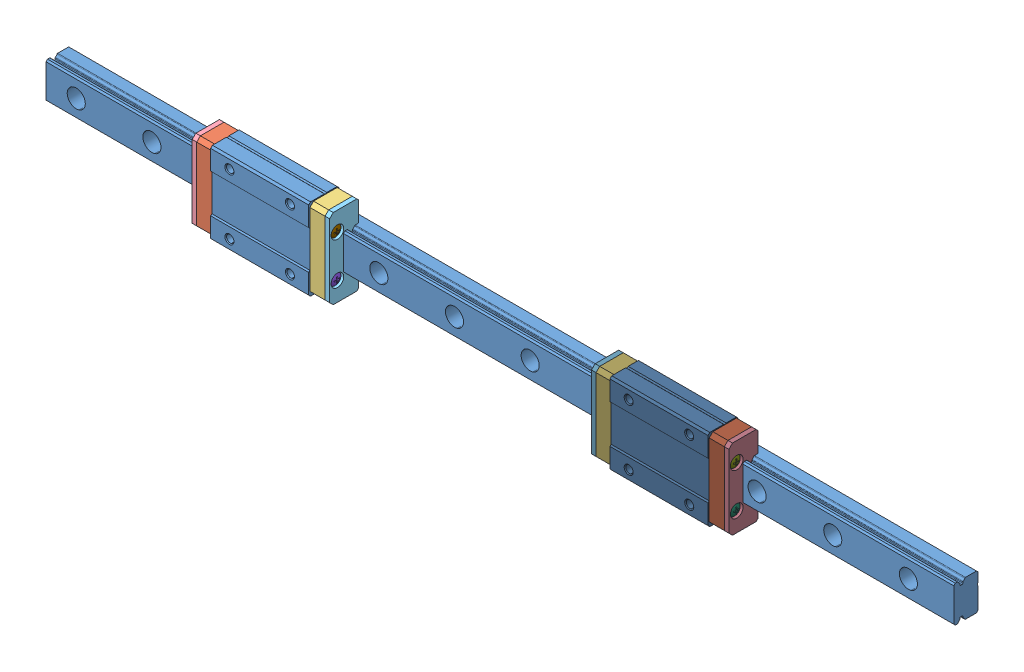
SolidWorks assembly MGN12H2R300ZFC-HiwinCorporation, configuration MGN12H2R300ZFC. Lengths in mm.
Overall size (300 27 13.07).
21 component instances, 19 part files, 9 mates.
Components (placement in the parent):
- Assem2^MGN12H2R300ZFC-HiwinCorporation-1: Assem2^MGN12H2R300ZFC-HiwinCorporation [Default] at (-16.8191 0 0) size (45.6 27 10) (virtual)
  - PRODUCT_ID_1_1-1: PRODUCT_ID_1_1 [Default] at origin size (32.4 27 10)
  - PRODUCT_ID_2_1-1: PRODUCT_ID_2_1 [Default] at origin size (5 26.4 9.6)
  - PRODUCT_ID_3_1-1: PRODUCT_ID_3_1 [Default] at origin size (5 26.4 9.6)
  - PRODUCT_ID_4_1-1: PRODUCT_ID_4_1 [Default] at origin size (1.5 26.4 9.6)
  - PRODUCT_ID_5_1-1: PRODUCT_ID_5_1 [Default] at origin size (1.5 26.4 9.6)
  - PRODUCT_ID_6_1-1: PRODUCT_ID_6_1 [Default] at origin size (1.7 4 4)
  - PRODUCT_ID_7_1-1: PRODUCT_ID_7_1 [Default] at origin size (1.7 4 4)
  - PRODUCT_ID_8_1-1: PRODUCT_ID_8_1 [Default] at origin size (1.7 4 4)
  - PRODUCT_ID_9_1-1: PRODUCT_ID_9_1 [Default] at origin size (1.7 4 4)
- Assem4^MGN12H2R300ZFC-HiwinCorporation-1: Assem4^MGN12H2R300ZFC-HiwinCorporation [Default] at origin size (45.6 27 10) (virtual)
  - PRODUCT_ID_10_1-1: PRODUCT_ID_10_1 [Default] at origin size (32.4 27 10)
  - PRODUCT_ID_11_1-1: PRODUCT_ID_11_1 [Default] at origin size (5 26.4 9.6)
  - PRODUCT_ID_12_1-1: PRODUCT_ID_12_1 [Default] at origin size (5 26.4 9.6)
  - PRODUCT_ID_13_1-1: PRODUCT_ID_13_1 [Default] at origin size (1.5 26.4 9.6)
  - PRODUCT_ID_14_1-1: PRODUCT_ID_14_1 [Default] at origin size (1.5 26.4 9.6)
  - PRODUCT_ID_15_1-1: PRODUCT_ID_15_1 [Default] at origin size (1.7 4 4)
  - PRODUCT_ID_16_1-1: PRODUCT_ID_16_1 [Default] at origin size (1.7 4 4)
  - PRODUCT_ID_17_1-1: PRODUCT_ID_17_1 [Default] at origin size (1.7 4 4)
  - PRODUCT_ID_18_1-1: PRODUCT_ID_18_1 [Default] at origin size (1.7 4 4)
- PRODUCT_ID_19-1: PRODUCT_ID_19 [Default] at origin size (300 12 8.07)
Mates (geometry in assembly coordinates):
- Coincident7: coincident aligned: plane of Assem2^MGN12H2R300ZFC-HiwinCorporation-1 through (-16.8191 0 0) normal (0 1 0)
- Parallel4: parallel aligned: plane of Assem2^MGN12H2R300ZFC-HiwinCorporation-1 through (-16.8191 0 0) normal (1 0 0)
- Coincident8: coincident aligned: plane of Assem2^MGN12H2R300ZFC-HiwinCorporation-1 through (-16.8191 0 0) normal (0 0 1)
- Coincident9: coincident aligned: plane of Assem4^MGN12H2R300ZFC-HiwinCorporation-1 through (0 0 0) normal (0 1 0)
- Coincident10: coincident aligned: plane of Assem4^MGN12H2R300ZFC-HiwinCorporation-1 through (0 0 0) normal (0 0 1)
- Parallel5: parallel aligned: plane of Assem4^MGN12H2R300ZFC-HiwinCorporation-1 through (0 0 0) normal (1 0 0)
- Coincident11: coincident aligned: plane of PRODUCT_ID_19-1 through (0 0 0) normal (0 0 1)
- Coincident12: coincident aligned: plane of PRODUCT_ID_19-1 through (0 0 0) normal (0 1 0)
- Coincident13: coincident aligned: plane of PRODUCT_ID_19-1 through (0 0 0) normal (1 0 0)
